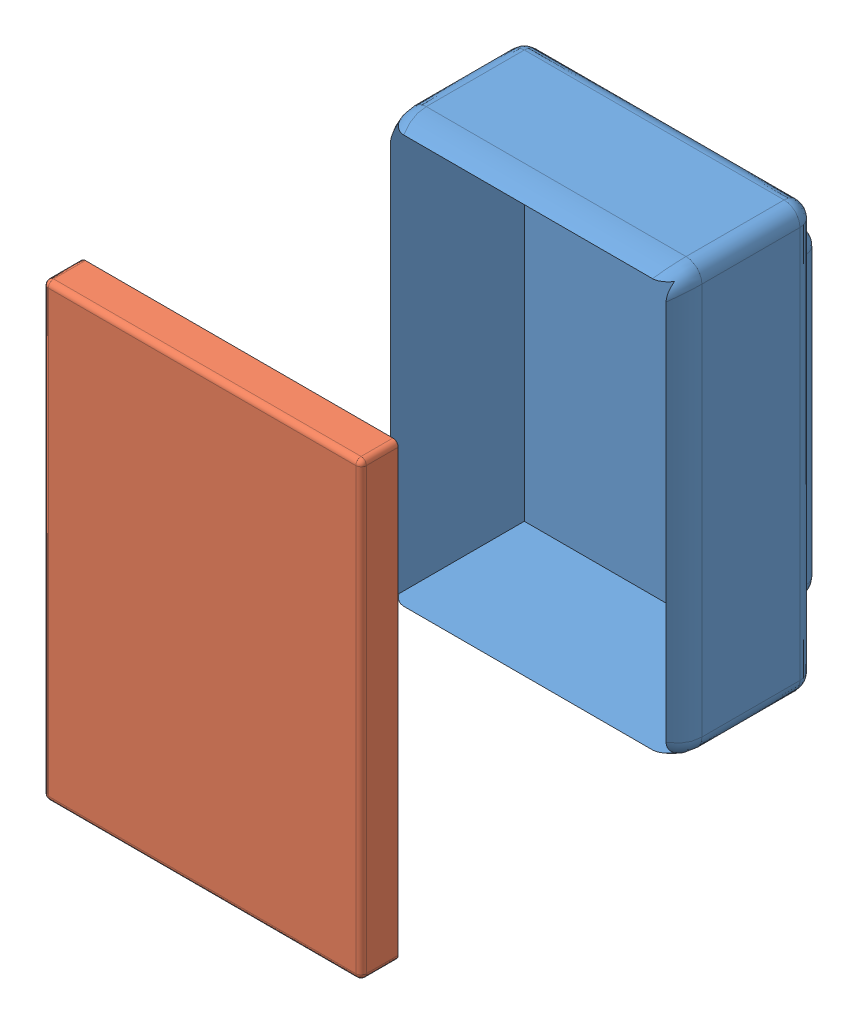
SolidWorks assembly Mont1, configuration Valor predeterminado. Lengths in mm.
Overall size (60 85 93.8).
2 component instances, 2 part files, 4 mates.
Components (placement in the parent):
- Bracelete_Pai-2: Bracelete_Pai [Valor predeterminado] at (-34.8762 -3.1503 80) size (55 80 33.05)
- Tampa_Bracelete_Pai-3: Tampa_Bracelete_Pai [Valor predeterminado] at (-50.3111 -4.6572 164.299) x (0 -1 0) z (0 0 -1) size (85 60 7)
Mates (geometry in assembly coordinates):
- Paralelo21: parallel anti-aligned: plane of Bracelete_Pai-2 through (-34.8762 -3.1503 80) normal (0 0 1); plane of Tampa_Bracelete_Pai-3 through (-50.3111 -4.6572 164.299) normal (0 0 -1)
- Coincidente36: coincident anti-aligned: plane of Bracelete_Pai-2 through (-5.6097 40.1061 110) normal (1 0 0); plane of Tampa_Bracelete_Pai-3 through (-5.6097 40.1061 159.299) normal (-1 0 0)
- Coincidente35: coincident anti-aligned: plane of Bracelete_Pai-2 through (-60.6097 40.1061 110) normal (0 1 0); plane of Tampa_Bracelete_Pai-3 through (-61.6097 40.1061 159.299) normal (0 -1 0)
- Paralelo24: parallel: line of Bracelete_Pai-2 through (-59.1097 36.0561 105.2678) axis (0 -1 0); plane of Tampa_Bracelete_Pai-3 through (-50.3111 -4.6572 164.299) normal (0 0 -1)
